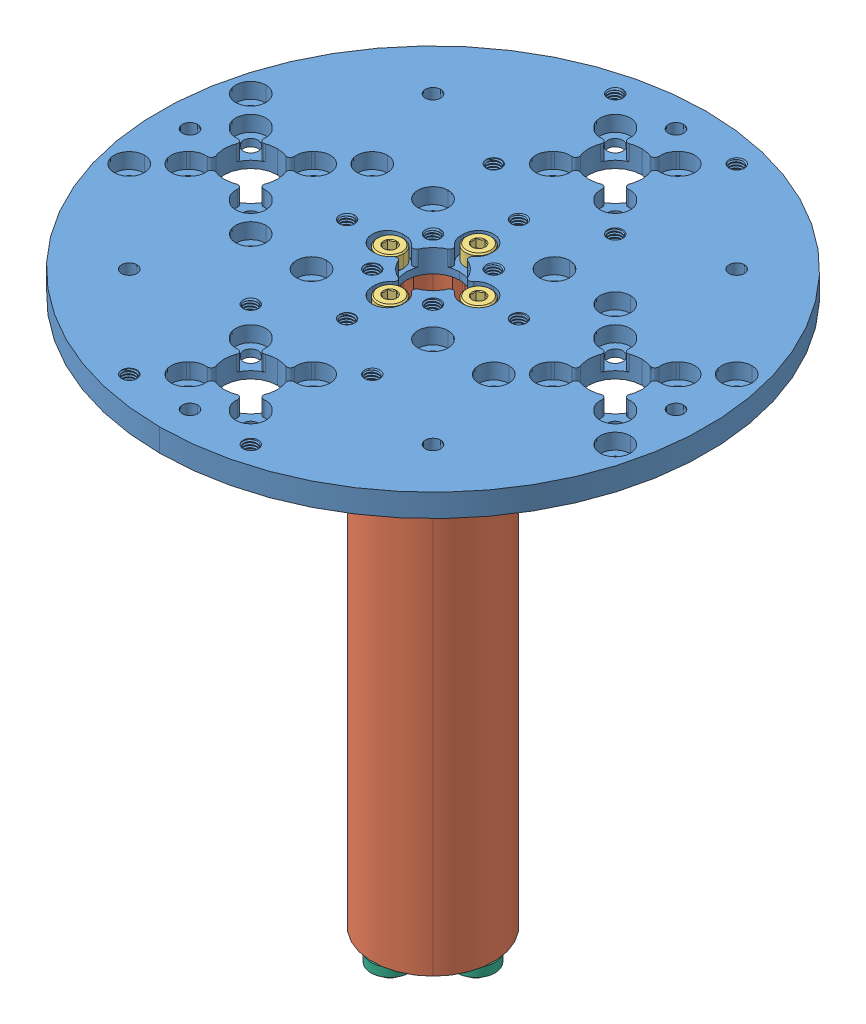
SolidWorks assembly Base_Assembly, configuration Default. Lengths in mm.
Overall size (144 154.61 144).
18 component instances, 8 part files, 38 mates.
Components (placement in the parent):
- 1140-0006-0144-1: 1140-0006-0144 [Default] at origin size (144 6.01 144)
- 4103-0032-0144-1: 4103-0032-0144 [Default] at (0 -144 0) x (0.707107 0 -0.707107) z (0.707107 0 0.707107) size (31.95 144 31.95)
- 2800-0004-0010-1: 2800-0004-0010 [Default] at (12 -8.1 0) x (1 0 0) z (0 -1 0) size (7 7 14.01)
- 2800-0004-0010-2: 2800-0004-0010 [Default] at (0 -8.1 11.3137) x (1 0 0) z (0 -1 0) size (7 7 14.01)
- 2800-0004-0010-3: 2800-0004-0010 [Default] at (-11.3137 -8.1 0) x (1 0 0) z (0 -1 0) size (7 7 14.01)
- 2800-0004-0010-4: 2800-0004-0010 [Default] at (0 -8.1 -12) x (1 0 0) z (0 -1 0) size (7 7 14.01)
- 2802-0004-0008-1: 2802-0004-0008 [Default] at (0 -148.6 11.3137) x (1 0 0) z (0 -1 0) size (7.6 7.6 10.21)
- 1506-0032-0006-1: 1506-0032-0006 [Default] at (0 -6 0) size (36 6 36)
- 98035A102_BLACK-OXIDE STEEL OVERSIZED FLAT WASHER-1: 98035A102_BLACK-OXIDE STEEL OVERSIZED FLAT WASHER [98035A102] at (11.3137 -144 0) x (1 0 0) z (0 -1 0) size (10 10 2.4)
- 98035A102_BLACK-OXIDE STEEL OVERSIZED FLAT WASHER-2: 98035A102_BLACK-OXIDE STEEL OVERSIZED FLAT WASHER [98035A102] at (0 -144 11.3137) x (1 0 0) z (0 -1 0) size (10 10 2.4)
- 98035A102_BLACK-OXIDE STEEL OVERSIZED FLAT WASHER-3: 98035A102_BLACK-OXIDE STEEL OVERSIZED FLAT WASHER [98035A102] at (-11.3137 -144 0) x (1 0 0) z (0 -1 0) size (10 10 2.4)
- 98035A102_BLACK-OXIDE STEEL OVERSIZED FLAT WASHER-4: 98035A102_BLACK-OXIDE STEEL OVERSIZED FLAT WASHER [98035A102] at (0 -144 -11.3137) x (1 0 0) z (0 -1 0) size (10 10 2.4)
- 2802-0004-0008-2: 2802-0004-0008 [Default] at (11.3137 -148.6 0) x (1 0 0) z (0 -1 0) size (7.6 7.6 10.21)
- 2802-0004-0008-3: 2802-0004-0008 [Default] at (-11.3137 -148.6 0) x (1 0 0) z (0 -1 0) size (7.6 7.6 10.21)
- 2802-0004-0008-4: 2802-0004-0008 [Default] at (0 -148.6 -11.3137) x (0.285736 0 -0.958309) z (0 -1 0) size (7.6 7.6 10.21)
- 1506-0032-0006-2: 1506-0032-0006 [Default] at (0 -12 0) size (36 6 36)
- 1506-0032-0004-1: 1506-0032-0004 [Default] at (0 -16 0) size (36 4 36)
- 1500-0010-0032-1: 1500-0010-0032 [Default] at (0 -17 0) size (34 1 34)
Mates (geometry in assembly coordinates):
- Coincident1: coincident aligned: plane of 1140-0006-0144-1 through (0 0 0) normal (0 1 0)
- Coincident2: coincident aligned: plane of 1140-0006-0144-1 through (0 0 0) normal (0 0 1)
- Coincident3: coincident aligned: plane of 1140-0006-0144-1 through (0 0 0) normal (1 0 0)
- Coincident7: coincident aligned: plane of 2800-0004-0010-1 through (12 1.9 0) normal (0 -1 0); plane of 2800-0004-0010-2 through (0 1.9 11.3137) normal (0 -1 0)
- Coincident8: coincident aligned: plane of 2800-0004-0010-1 through (12 1.9 0) normal (0 -1 0); plane of 2800-0004-0010-3 through (-11.3137 1.9 0) normal (0 -1 0)
- Coincident9: coincident aligned: plane of 2800-0004-0010-1 through (12 1.9 0) normal (0 -1 0); plane of 2800-0004-0010-4 through (0 1.9 -12) normal (0 -1 0)
- Concentric4: concentric anti-aligned: cylinder of 1140-0006-0144-1 through (0 1.9 11.3137) axis (0 1 0) radius 4; cylinder of 2800-0004-0010-2 through (0 5.9 11.3137) axis (0 -1 0) radius 3.5
- Coincident10: coincident anti-aligned: plane of 1140-0006-0144-1 through (0 1.9 0) normal (0 1 0); plane of 2800-0004-0010-1 through (12 1.9 0) normal (0 -1 0)
- Concentric5: concentric anti-aligned: cylinder of 1140-0006-0144-1 through (12 1.9 0) axis (0 1 0) radius 4; cylinder of 2800-0004-0010-1 through (12 5.9 0) axis (0 -1 0) radius 3.5
- Concentric6: concentric anti-aligned: cylinder of 1140-0006-0144-1 through (0 1.9 -12) axis (0 1 0) radius 4; cylinder of 2800-0004-0010-4 through (0 5.9 -12) axis (0 -1 0) radius 3.5
- Concentric7: concentric anti-aligned: cylinder of 1140-0006-0144-1 through (-11.3137 1.9 0) axis (0 1 0) radius 4; cylinder of 2800-0004-0010-3 through (-11.3137 5.9 0) axis (0 -1 0) radius 3.5
- Coincident12: coincident aligned: plane of 98035A102_BLACK-OXIDE STEEL OVERSIZED FLAT WASHER-2 through (0 -144 11.3137) normal (0 1 0); plane of 98035A102_BLACK-OXIDE STEEL OVERSIZED FLAT WASHER-4 through (0 -144 -11.3137) normal (0 1 0)
- Coincident13: coincident aligned: plane of 98035A102_BLACK-OXIDE STEEL OVERSIZED FLAT WASHER-3 through (-11.3137 -144 0) normal (0 1 0); plane of 98035A102_BLACK-OXIDE STEEL OVERSIZED FLAT WASHER-4 through (0 -144 -11.3137) normal (0 1 0)
- Coincident14: coincident aligned: plane of 98035A102_BLACK-OXIDE STEEL OVERSIZED FLAT WASHER-1 through (11.3137 -144 0) normal (0 1 0); plane of 98035A102_BLACK-OXIDE STEEL OVERSIZED FLAT WASHER-2 through (0 -144 11.3137) normal (0 1 0)
- Coincident15: coincident aligned: plane of 2802-0004-0008-3 through (-11.3137 -146.4 -3.8) normal (0 1 0); plane of 2802-0004-0008-4 through (-3.6416 -146.4 -12.3995) normal (0 1 0)
- Coincident16: coincident aligned: plane of 2802-0004-0008-2 through (11.3137 -146.4 -3.8) normal (0 1 0); plane of 2802-0004-0008-3 through (-11.3137 -146.4 -3.8) normal (0 1 0)
- Coincident17: coincident aligned: plane of 2802-0004-0008-1 through (0 -146.4 7.5137) normal (0 1 0); plane of 2802-0004-0008-3 through (-11.3137 -146.4 -3.8) normal (0 1 0)
- Coincident18: coincident anti-aligned: plane of 2802-0004-0008-1 through (0 -146.4 7.5137) normal (0 1 0); plane of 98035A102_BLACK-OXIDE STEEL OVERSIZED FLAT WASHER-1 through (11.3137 -146.4 0) normal (0 -1 0)
- Concentric9: concentric anti-aligned: cylinder of 98035A102_BLACK-OXIDE STEEL OVERSIZED FLAT WASHER-1 through (11.3137 -146.4 0) axis (0 1 0) radius 5; cylinder of 2802-0004-0008-2 through (11.3137 -148.6 0) axis (0 -1 0) radius 3.8
- Concentric10: concentric anti-aligned: cylinder of 2802-0004-0008-1 through (0 -148.6 11.3137) axis (0 -1 0) radius 3.8; cylinder of 98035A102_BLACK-OXIDE STEEL OVERSIZED FLAT WASHER-2 through (0 -146.4 11.3137) axis (0 1 0) radius 5
- Concentric11: concentric anti-aligned: cylinder of 98035A102_BLACK-OXIDE STEEL OVERSIZED FLAT WASHER-4 through (0 -146.4 -11.3137) axis (0 1 0) radius 5; cylinder of 2802-0004-0008-4 through (0 -148.6 -11.3137) axis (0 -1 0) radius 3.8
- Concentric12: concentric anti-aligned: cylinder of 98035A102_BLACK-OXIDE STEEL OVERSIZED FLAT WASHER-3 through (-11.3137 -146.4 0) axis (0 1 0) radius 5; cylinder of 2802-0004-0008-3 through (-11.3137 -148.6 0) axis (0 -1 0) radius 3.8
- Concentric13: concentric aligned: cylinder of 1140-0006-0144-1 through (0 6 0) axis (0 -1 0) radius 7; cylinder of 4103-0032-0144-1 through (0 0 0) axis (0 -1 0) radius 15.975
- Coincident19: coincident anti-aligned: plane of 1140-0006-0144-1 through (0 0 0) normal (0 -1 0); plane of 4103-0032-0144-1 through (0 0 0) normal (0 1 0)
- Concentric15: concentric anti-aligned: cylinder of 4103-0032-0144-1 through (-11.3137 0 0) axis (0 -1 0) radius 2.7; cylinder of 1140-0006-0144-1 through (-11.3137 0 0) axis (0 1 0) radius 2.025
- Concentric16: concentric anti-aligned: cylinder of 4103-0032-0144-1 through (-11.3137 0 0) axis (0 -1 0) radius 2.7; cylinder of 98035A102_BLACK-OXIDE STEEL OVERSIZED FLAT WASHER-3 through (-11.3137 -146.4 0) axis (0 1 0) radius 5
- Coincident20: coincident anti-aligned: plane of 4103-0032-0144-1 through (0 -144 0) normal (0 -1 0); plane of 98035A102_BLACK-OXIDE STEEL OVERSIZED FLAT WASHER-3 through (-11.3137 -144 0) normal (0 1 0)
- Concentric17: concentric anti-aligned: cylinder of 4103-0032-0144-1 through (0 0 11.3137) axis (0 -1 0) radius 2.7; cylinder of 98035A102_BLACK-OXIDE STEEL OVERSIZED FLAT WASHER-2 through (0 -146.4 11.3137) axis (0 1 0) radius 5
- Concentric18: concentric anti-aligned: cylinder of 4103-0032-0144-1 through (0 0 -11.3137) axis (0 -1 0) radius 2.7; cylinder of 98035A102_BLACK-OXIDE STEEL OVERSIZED FLAT WASHER-4 through (0 -146.4 -11.3137) axis (0 1 0) radius 5
- Concentric19: concentric anti-aligned: cylinder of 4103-0032-0144-1 through (11.3137 0 0) axis (0 -1 0) radius 2.7; cylinder of 98035A102_BLACK-OXIDE STEEL OVERSIZED FLAT WASHER-1 through (11.3137 -146.4 0) axis (0 1 0) radius 5
- Concentric20: concentric aligned: cylinder of 4103-0032-0144-1 through (0 0 0) axis (0 -1 0) radius 15.975; cylinder of 1506-0032-0006-1 through (0 0 0) axis (0 -1 0) radius 18
- Coincident21: coincident anti-aligned: plane of 1140-0006-0144-1 through (0 0 0) normal (0 -1 0); plane of 1506-0032-0006-1 through (0 0 0) normal (0 1 0)
- Concentric21: concentric aligned: cylinder of 4103-0032-0144-1 through (0 0 0) axis (0 -1 0) radius 15.975; cylinder of 1506-0032-0006-2 through (0 -6 0) axis (0 -1 0) radius 18
- Coincident22: coincident anti-aligned: plane of 1506-0032-0006-1 through (0 -6 0) normal (0 -1 0); plane of 1506-0032-0006-2 through (0 -6 0) normal (0 1 0)
- Concentric22: concentric aligned: cylinder of 4103-0032-0144-1 through (0 0 0) axis (0 -1 0) radius 15.975; cylinder of 1506-0032-0004-1 through (0 -12 0) axis (0 -1 0) radius 18
- Coincident23: coincident anti-aligned: plane of 1506-0032-0006-2 through (0 -12 0) normal (0 -1 0); plane of 1506-0032-0004-1 through (0 -12 0) normal (0 1 0)
- Concentric23: concentric aligned: cylinder of 4103-0032-0144-1 through (0 0 0) axis (0 -1 0) radius 15.975; cylinder of 1500-0010-0032-1 through (0 -16 0) axis (0 -1 0) radius 17
- Coincident24: coincident anti-aligned: plane of 1506-0032-0004-1 through (0 -16 0) normal (0 -1 0); plane of 1500-0010-0032-1 through (0 -16 0) normal (0 1 0)
